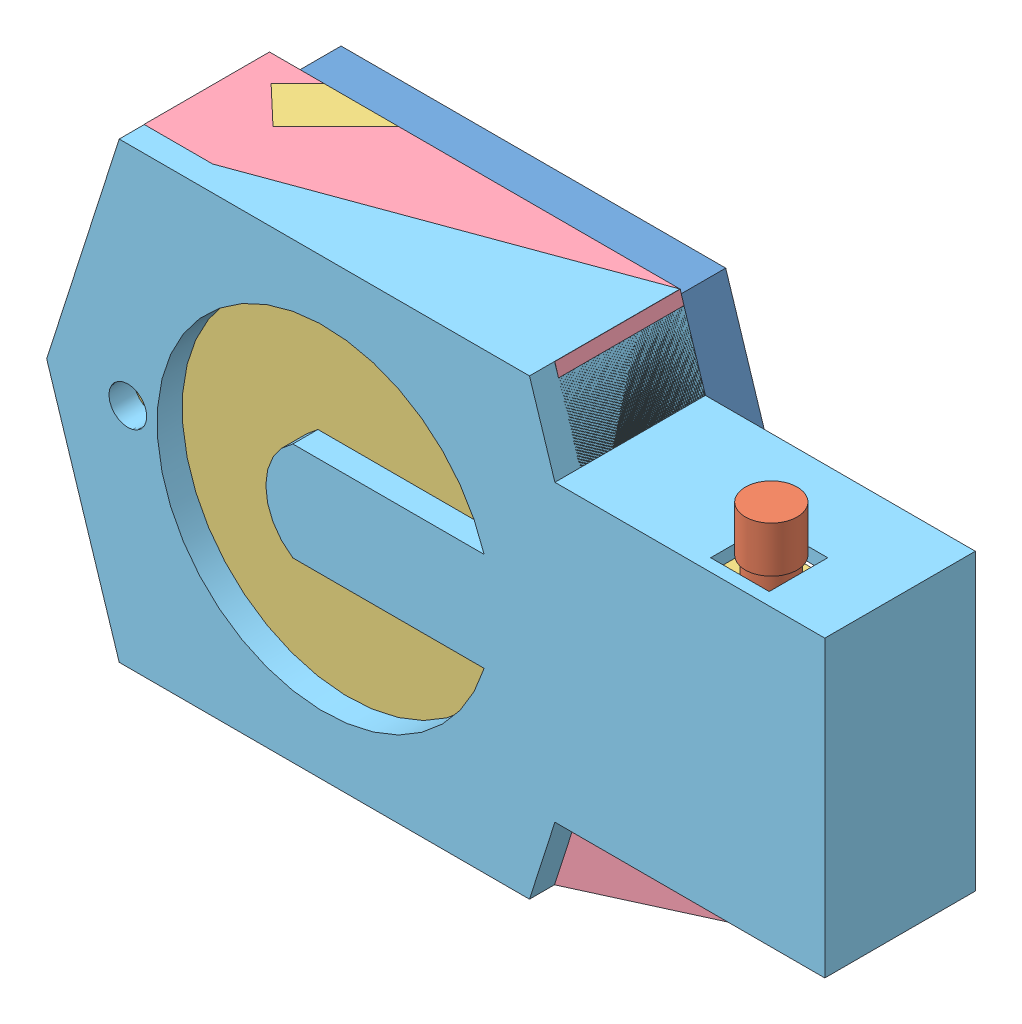
SolidWorks assembly sensor_asm_r1, configuration Default. Lengths in mm.
Overall size (93.05 54.2 25).
5 component instances, 5 part files, 2 mates.
Components (placement in the parent):
- indicador-1: indicador [Default] at origin size (62 50 16)
- pcb-1: pcb [Default] at (29.75 0 18) size (60 37.5 14.8)
- case_test_r1-1: case_test_r1 [Default] at origin size (93.05 54.2 15) (hidden)
- case_cpt_r1-1: case_cpt_r1 [Default] at origin size (92.29 54.2 17) (hidden)
- case_cpt_r2-1: case_cpt_r2 [Default] at origin size (93.05 54.2 18)
Mates (geometry in assembly coordinates):
- Concentric1: concentric: cylinder of indicador-1 through (23.75 0 16) axis (0 0 -1) radius 3.5; cylinder of pcb-1 through (23.75 0 19.6) axis (0 0 -1) radius 1.75
- Distance1: distance = 2 mm: plane of pcb-1 through (29.75 0 18) normal (0 0 -1); plane of indicador-1 through (0 0 16) normal (0 0 1)
